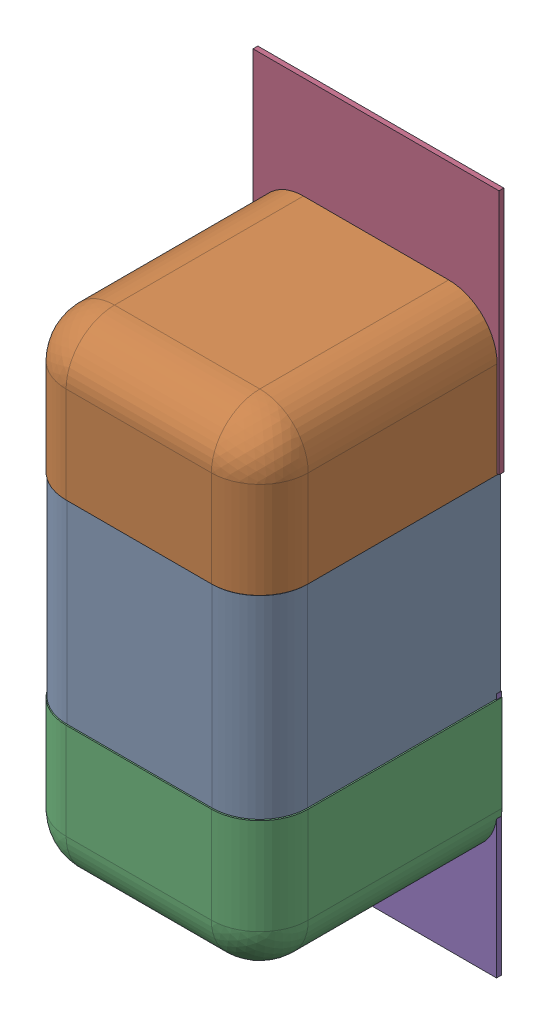
SolidWorks assembly C142, configuration Défaut. Lengths in mm.
Overall size (0.51 1.41 0.5).
8 component instances, 4 part files, 0 mates.
Components (placement in the parent):
- 6501210464-1: 6501210464 [Défaut] at (15.3488 -20.9804 0) x (0 -1 0) z (-1 0 0) size (1 0.5 0.5)
  - Open CASCADE STEP translator 7.5 2.33.1.1-1: Open CASCADE STEP translator 7.5 2.33.1.1 [Défaut] at origin size (0.4 0.5 0.5)
  - Open CASCADE STEP translator 7.5 2.33.1.2-1: Open CASCADE STEP translator 7.5 2.33.1.2 [Défaut] at origin size (0.3 0.5 0.5)
  - Open CASCADE STEP translator 7.5 2.33.1.3-1: Open CASCADE STEP translator 7.5 2.33.1.3 [Défaut] at origin size (0.3 0.5 0.5)
- 6504207776-1: 6504207776 [Défaut] at (15.3487 -20.5231 0) size (0.51 0.51 0.01)
  - Extruded-1: Extruded [Défaut] at origin size (0.51 0.51 0.01)
- 6504207776-2: 6504207776 [Défaut] at (15.3436 -21.4254 0) size (0.51 0.51 0.01)
  - Extruded-1: Extruded [Défaut] at origin size (0.51 0.51 0.01)
